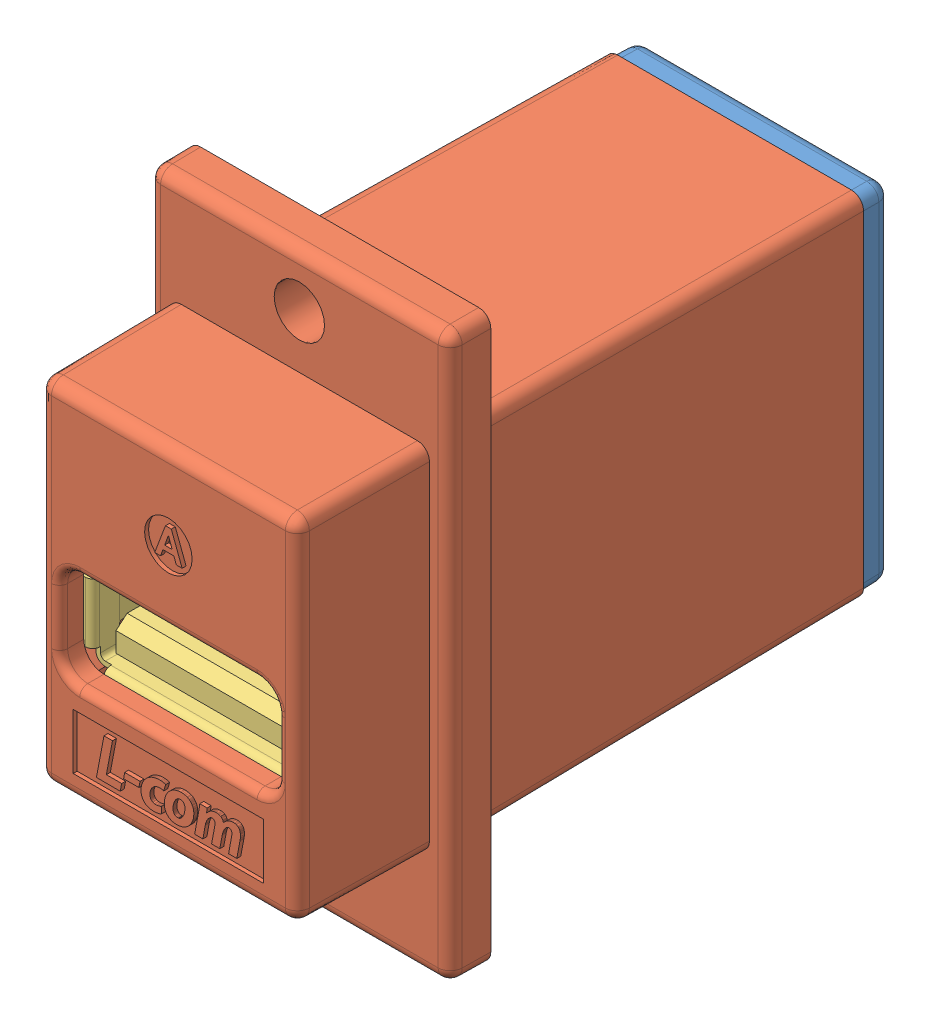
SolidWorks assembly Surge Protector, configuration Default. Lengths in mm.
Overall size (19.05 35.56 37.54).
5 component instances, 4 part files, 0 mates.
Components (placement in the parent):
- 1AG01-019_TYPE B-1: 1AG01-019_TYPE B [Default] at (0 0 -21.8867) size (16 21.84 4.78)
- 1AG01-020_TYPE A-1: 1AG01-020_TYPE A [Default] at (0 0 3.0815) size (19.05 35.56 35.69)
- 3AC11-010___-1: 3AC11-010___ [Default] at (0 3.8352 -4.5775) x (0 0 1) z (1 0 0) size (33.53 9.83 14.5)
  - 1AA05-019-SUZHOU___-1: 1AA05-019-SUZHOU___ [Default] at (3.13 5.8 0) x (0 0 -1) z (1 0 0) size (14.5 9.83 14.2)
  - 1BC01-017+COMPONENT_Rev.-1: 1BC01-017+COMPONENT_Rev. [Default] at origin size (33.2 2.1 12.7)
